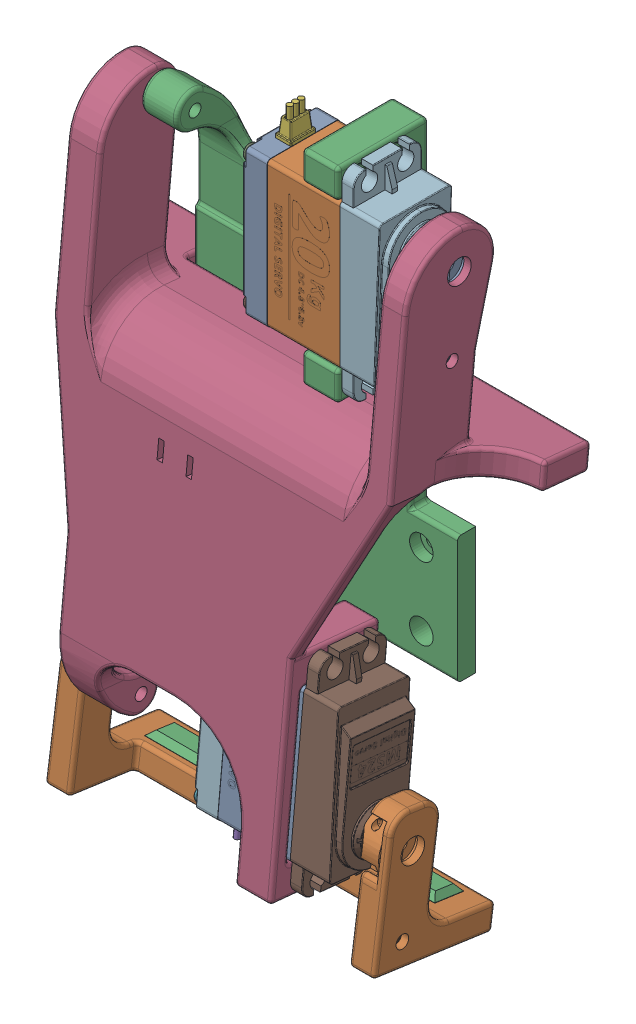
SolidWorks assembly Assemblage_Pince_A_Planche, configuration Défaut. Lengths in mm.
Overall size (123 180.65 56.22).
10 component instances, 8 part files, 25 mates.
Components (placement in the parent):
- Servo_Arm_MS24-1: Servo_Arm_MS24 [Default] at (21 0 0) x (0 -0.096902 -0.995294) z (0 -0.995294 0.096902) size (14.5 6.15 35.53)
- Servo_Arm_MS24-2: Servo_Arm_MS24 [Default] at (21 -132.0755 12.8588) x (0 -0.140082 -0.99014) z (0 -0.99014 0.140082) size (14.5 6.15 35.53)
- Digital_Servo_MS24_270-2: Digital_Servo_MS24_270 [Default] at (0 -132.0755 12.8588) x (0 0.096902 0.995294) z (0 0.995294 -0.096902) size (20.1 45.99 55.6)
- Pince_A_Planche_Pince-1: Pince_A_Planche_Pince [Défaut] at (-23.5 -153.6994 2.7887) x (1 0 0) z (0 -0.99014 0.140082) size (93 33 37)
- Patin_Pince-1: Patin_Pince [Défaut] at (-23.5 -156.5902 -3.3671) x (1 0 0) z (0 -0.140082 -0.99014) size (80 3.5 8)
- Digital_Servo_MS24_270-3: Digital_Servo_MS24_270 [Default] x (0 0 -1) z (0 -1 0) size (20.1 45.99 55.6)
- Support_Servo_Pince_A_Planche-1: Support_Servo_Pince_A_Planche [Défaut] at (0 -10 0) size (73 126.4 25)
- Bras_Pince_A_Planche-1: Bras_Pince_A_Planche [Défaut] at (0 -122.1226 11.8898) x (1 0 0) z (0 -0.995294 0.096902) size (123 40.82 160.96)
- Patin_Pince_Moyen-1: Patin_Pince_Moyen [Défaut] at (3.5 -48.1349 -14.534) x (0 -0.096902 -0.995294) z (1 0 0) size (8 3.5 32)
- Patin_Pince_Petit-1: Patin_Pince_Petit [Défaut] at (-82.5 -48.1349 -14.534) x (0 -0.096902 -0.995294) z (1 0 0) size (8 3.5 19)
Mates (geometry in assembly coordinates):
- Distance2: distance = 8.5 mm aligned: plane of Servo_Arm_MS24-2 through (21 -140.3903 27.9726) normal (1 0 0); plane of Digital_Servo_MS24_270-2 through (12.5 -140.161 22.6886) normal (1 0 0)
- Coaxiale2: concentric anti-aligned: cylinder of Servo_Arm_MS24-2 through (15 -132.0755 12.8588) axis (1 0 0) radius 7.25; circle of Digital_Servo_MS24_270-2
- Coaxiale3: concentric aligned: cylinder of Servo_Arm_MS24-2 through (15 -132.0755 12.8588) axis (1 0 0) radius 7.25; cylinder of Pince_A_Planche_Pince-1 through (16 -132.0755 12.8588) axis (1 0 0) radius 3.25
- Coaxiale4: concentric aligned: circle of Servo_Arm_MS24-2; cylinder of Pince_A_Planche_Pince-1 through (16 -152.3734 15.7305) axis (1 0 0) radius 1.75
- Coïncidente2: coincident anti-aligned: plane of Servo_Arm_MS24-2 through (21 -140.3903 27.9726) normal (1 0 0); plane of Pince_A_Planche_Pince-1 through (21 -153.6994 2.7887) normal (-1 0 0)
- Coïncidente4: coincident anti-aligned: plane of Pince_A_Planche_Pince-1 through (-23.5 -155.6797 3.0688) normal (0 0.99014 -0.140082); plane of Patin_Pince-1 through (-63.5 -157.1505 -7.3276) normal (0 -0.99014 0.140082)
- Distance3: distance = 0.1 mm anti-aligned: plane of Pince_A_Planche_Pince-1 through (-63.6 -156.0158 0.6925) normal (1 0 0); plane of Patin_Pince-1 through (-63.5 -156.5902 -3.3671) normal (-1 0 0)
- Distance4: distance = 0.1 mm anti-aligned: plane of Patin_Pince-1 through (-63.5 -155.1702 -7.6078) normal (0 -0.140082 -0.99014); plane of Pince_A_Planche_Pince-1 through (-63.6 -157.1645 -7.4267) normal (0 0.140082 0.99014)
- Coaxiale7: concentric anti-aligned: cylinder of Servo_Arm_MS24-1 through (15 0 0) axis (1 0 0) radius 7.25; circle of Digital_Servo_MS24_270-3
- Distance7: distance = 8.5 mm aligned: plane of Servo_Arm_MS24-1 through (21 -8.9641 14.738) normal (1 0 0); plane of Digital_Servo_MS24_270-3 through (12.5 9 -9) normal (1 0 0)
- Coaxiale8: concentric aligned: cylinder of Digital_Servo_MS24_270-3 through (-6.364 14 -5) axis (1 0 0) radius 2.25; cylinder of Support_Servo_Pince_A_Planche-1 through (-10 14 -5) axis (1 0 0) radius 2.25
- Coaxiale9: concentric aligned: cylinder of Digital_Servo_MS24_270-3 through (-6.364 14 5) axis (1 0 0) radius 2.25; cylinder of Support_Servo_Pince_A_Planche-1 through (-10 14 5) axis (1 0 0) radius 2.25
- Coïncidente10: coincident anti-aligned: plane of Digital_Servo_MS24_270-3 through (0 -27 -9) normal (-1 0 0); plane of Support_Servo_Pince_A_Planche-1 through (0 -10 0) normal (1 0 0)
- Coaxiale10: concentric aligned: cylinder of Servo_Arm_MS24-1 through (15 0 0) axis (1 0 0) radius 7.25; cylinder of Bras_Pince_A_Planche-1 through (16 0 0) axis (1 0 0) radius 3.25
- Coaxiale11: concentric aligned: circle of Servo_Arm_MS24-1; cylinder of Bras_Pince_A_Planche-1 through (16 -20.4035 1.9865) axis (1 0 0) radius 1.65
- Coïncidente11: coincident anti-aligned: plane of Servo_Arm_MS24-1 through (21 -8.9641 14.738) normal (1 0 0); plane of Bras_Pince_A_Planche-1 through (21 0 0) normal (-1 0 0)
- Coaxiale12: concentric aligned: cylinder of Digital_Servo_MS24_270-2 through (-6.364 -145.5251 19.1919) axis (1 0 0) radius 2.25; cylinder of Bras_Pince_A_Planche-1 through (-10 -145.5251 19.1919) axis (1 0 0) radius 2.25
- Coaxiale13: concentric aligned: cylinder of Digital_Servo_MS24_270-2 through (-6.364 -146.4941 9.239) axis (1 0 0) radius 2.25; cylinder of Bras_Pince_A_Planche-1 through (-10 -146.4941 9.239) axis (1 0 0) radius 2.25
- Coïncidente12: coincident anti-aligned: plane of Digital_Servo_MS24_270-2 through (0 -104.3305 19.2001) normal (-1 0 0); plane of Bras_Pince_A_Planche-1 through (0 -122.1226 11.8898) normal (1 0 0)
- Coïncidente16: coincident anti-aligned: plane of Bras_Pince_A_Planche-1 through (0 -46.2812 4.5059) normal (0 -0.995294 0.096902); plane of Patin_Pince_Petit-1 through (-63.5 -47.7473 -10.5529) normal (0 0.995294 -0.096902)
- Coïncidente17: coincident anti-aligned: plane of Bras_Pince_A_Planche-1 through (0 -46.2812 4.5059) normal (0 -0.995294 0.096902); plane of Patin_Pince_Moyen-1 through (35.5 -47.7473 -10.5529) normal (0 0.995294 -0.096902)
- Distance10: distance = 0.1 mm anti-aligned: plane of Patin_Pince_Moyen-1 through (35.5 -48.5225 -18.5152) normal (0 -0.096902 -0.995294); plane of Bras_Pince_A_Planche-1 through (3.4 -48.5322 -18.6148) normal (0 0.096902 0.995294)
- Distance11: distance = 0.1 mm anti-aligned: plane of Patin_Pince_Moyen-1 through (35.5 -48.1349 -14.534) normal (1 0 0); plane of Bras_Pince_A_Planche-1 through (35.6 -48.5322 -18.6148) normal (-1 0 0)
- Distance12: distance = 0.1 mm anti-aligned: plane of Bras_Pince_A_Planche-1 through (-63.4 -47.7376 -10.4533) normal (-1 0 0); plane of Patin_Pince_Petit-1 through (-63.5 -48.1349 -14.534) normal (1 0 0)
- Distance13: distance = 0.1 mm anti-aligned: plane of Bras_Pince_A_Planche-1 through (-82.6 -48.5322 -18.6148) normal (0 0.096902 0.995294); plane of Patin_Pince_Petit-1 through (-63.5 -48.5225 -18.5152) normal (0 -0.096902 -0.995294)
